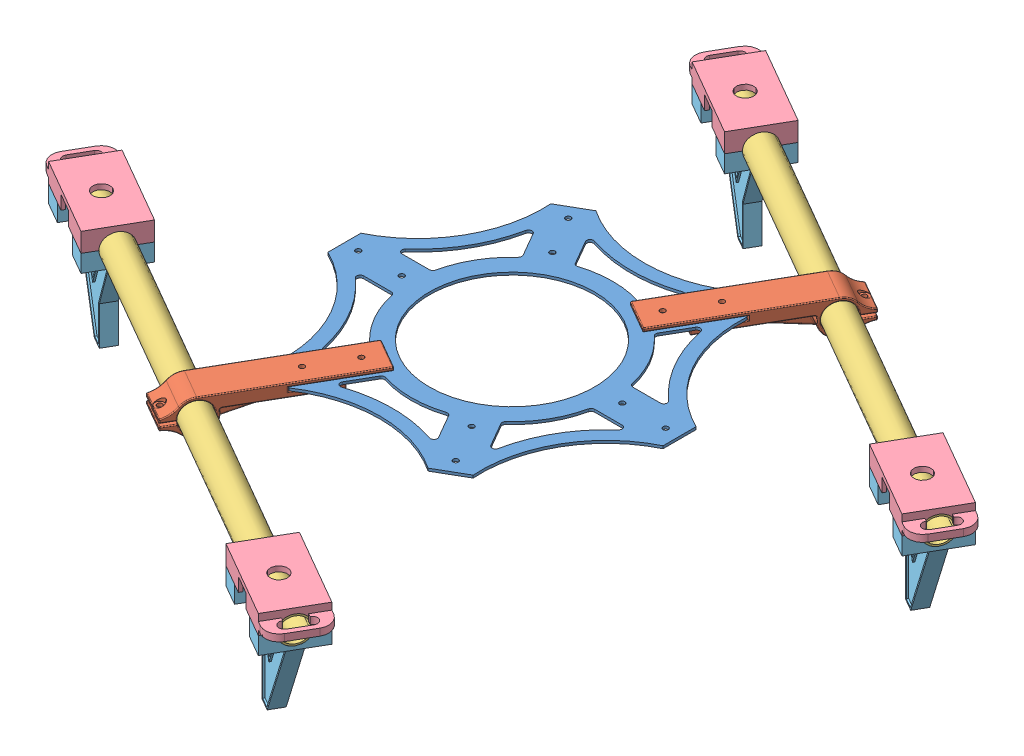
SolidWorks assembly Assem2, configuration По умолчанию. Lengths in mm.
Overall size (455.98 70 437.77).
17 component instances, 5 part files, 22 mates.
Components (placement in the parent):
- centralplate-1: centralplate [По умолчанию] at origin size (193 1.5 176.64)
- tubetoplate-4: tubetoplate [По умолчанию] at (59.1575 -5.8 -122.4638) x (0.866025 0 0.5) z (-0.5 0 0.866025) size (20 20 98.99)
- tubetoplate-5: tubetoplate [По умолчанию] at (-59.1575 -5.8 122.4638) x (-0.866025 0 -0.5) z (0.5 0 -0.866025) size (20 20 98.99)
- carbontube-1: carbontube [По умолчанию] at (67.8178 -5.8 -117.4638) x (0.5 0 -0.866025) z (0.866025 0 0.5) size (16 16 330)
- carbontube-2: carbontube [По умолчанию] at (-67.8178 -5.8 117.4638) x (0.5 0 -0.866025) z (0.866025 0 0.5) size (16 16 330)
- motor_assembl-2: motor_assembl [По умолчанию] at (10.2103 -44.14 186.8516) x (0.5 0 -0.866025) z (0.866025 0 0.5) size (31 70 62)
  - motorhandle-top-1: motorhandle-top [По умолчанию] at (21.0775 49.34 37.2318) size (31 11.52 62)
  - motorhandle-bottom-1: motorhandle-bottom [По умолчанию] at (21.0775 28.34 37.2318) x (0 0 -1) z (1 0 0) size (51 59 31)
- motor_assembl-3: motor_assembl [По умолчанию] at (145.8459 -44.14 -48.0761) x (0.5 0 -0.866025) z (0.866025 0 0.5) size (31 70 62)
  - motorhandle-top-1: motorhandle-top [По умолчанию] at (21.0775 49.34 37.2318) size (31 11.52 62)
  - motorhandle-bottom-1: motorhandle-bottom [По умолчанию] at (21.0775 28.34 37.2318) x (0 0 -1) z (1 0 0) size (51 59 31)
- motor_assembl-4: motor_assembl [По умолчанию] at (-145.8459 -44.14 48.0761) x (-0.5 0 0.866025) z (-0.866025 0 -0.5) size (31 70 62)
  - motorhandle-top-1: motorhandle-top [По умолчанию] at (21.0775 49.34 37.2318) size (31 11.52 62)
  - motorhandle-bottom-1: motorhandle-bottom [По умолчанию] at (21.0775 28.34 37.2318) x (0 0 -1) z (1 0 0) size (51 59 31)
- motor_assembl-5: motor_assembl [По умолчанию] at (-10.2103 -44.14 -186.8516) x (-0.5 0 0.866025) z (-0.866025 0 -0.5) size (31 70 62)
  - motorhandle-top-1: motorhandle-top [По умолчанию] at (21.0775 49.34 37.2318) size (31 11.52 62)
  - motorhandle-bottom-1: motorhandle-bottom [По умолчанию] at (21.0775 28.34 37.2318) x (0 0 -1) z (1 0 0) size (51 59 31)
Mates (geometry in assembly coordinates):
- Distance1: distance = 0 mm anti-aligned: plane of centralplate-1 through (-128.467 0 -74.1705) normal (0 -1 0); plane of tubetoplate-4 through (57.1603 0 -79.0045) normal (0 1 0)
- Concentric2: concentric aligned: circle of centralplate-1; circle of tubetoplate-4
- Concentric4: concentric aligned: circle of centralplate-1; circle of tubetoplate-4
- Distance2: distance = 0 mm anti-aligned: plane of centralplate-1 through (-128.467 0 -74.1705) normal (0 -1 0); plane of tubetoplate-5 through (-57.1603 0 79.0045) normal (0 1 0)
- Concentric5: concentric aligned: circle of centralplate-1; circle of tubetoplate-5
- Concentric6: concentric aligned: circle of centralplate-1; circle of tubetoplate-5
- Concentric7: concentric aligned: circle of tubetoplate-4; circle of carbontube-1
- Distance3: distance = 155 mm aligned: plane of carbontube-1 through (210.712 -5.8 -34.9638) normal (0.866025 0 0.5); plane of tubetoplate-4 through (76.478 -5.8 -112.4638) normal (0.866025 0 0.5)
- Concentric8: concentric anti-aligned: circle of tubetoplate-5; circle of carbontube-2
- Distance5: distance = 155 mm aligned: plane of carbontube-2 through (75.0764 -5.8 199.9638) normal (0.866025 0 0.5); plane of tubetoplate-5 through (-59.1575 -5.8 122.4638) normal (0.866025 0 0.5)
- Distance7: distance = 0 mm aligned: plane of carbontube-2 through (75.0764 -5.8 199.9638) normal (0.866025 0 0.5); plane of motor_assembl-2/motorhandle-bottom-1 through (67.3264 -5.8 213.3872) normal (0.866025 0 0.5)
- Concentric11: concentric aligned: circle of carbontube-2; circle of motor_assembl-2/motorhandle-top-1
- Distance8: distance = 0 mm aligned: plane of carbontube-1 through (210.712 -5.8 -34.9638) normal (0.866025 0 0.5); plane of motor_assembl-3/motorhandle-bottom-1 through (202.962 -5.8 -21.5404) normal (0.866025 0 0.5)
- Concentric12: concentric aligned: circle of carbontube-1; circle of motor_assembl-3/motorhandle-top-1
- Parallel12: parallel aligned: plane of centralplate-1 through (-128.467 1.5 -74.1705) normal (0 1 0); plane of motor_assembl-3/motorhandle-top-1 through (188.6283 5.2001 -47.7138) normal (0 1 0)
- Parallel13: parallel aligned: plane of centralplate-1 through (-128.467 1.5 -74.1705) normal (0 1 0); plane of motor_assembl-2/motorhandle-top-1 through (52.9928 5.2001 187.2138) normal (0 1 0)
- Parallel14: parallel aligned: plane of centralplate-1 through (-128.467 1.5 -74.1705) normal (0 1 0); plane of motor_assembl-5/motorhandle-top-1 through (-86.118 5.2001 -206.3387) normal (0 1 0)
- Parallel15: parallel aligned: plane of centralplate-1 through (-128.467 1.5 -74.1705) normal (0 1 0); plane of motor_assembl-4/motorhandle-top-1 through (-173.9125 5.2001 56.21) normal (0 1 0)
- Concentric16: concentric anti-aligned: circle of carbontube-1; circle of motor_assembl-5/motorhandle-top-1
- Distance11: distance = 0 mm aligned: plane of carbontube-1 through (-75.0764 -5.8 -199.9638) normal (-0.866025 0 -0.5); plane of motor_assembl-5/motorhandle-bottom-1 through (-67.3264 -5.8 -213.3872) normal (-0.866025 0 -0.5)
- Concentric17: concentric anti-aligned: circle of carbontube-2; circle of motor_assembl-4/motorhandle-top-1
- Distance12: distance = 0 mm aligned: plane of carbontube-2 through (-210.712 -5.8 34.9638) normal (-0.866025 0 -0.5); plane of motor_assembl-4/motorhandle-top-1 through (-218.462 -5.8 48.3872) normal (-0.866025 0 -0.5)
